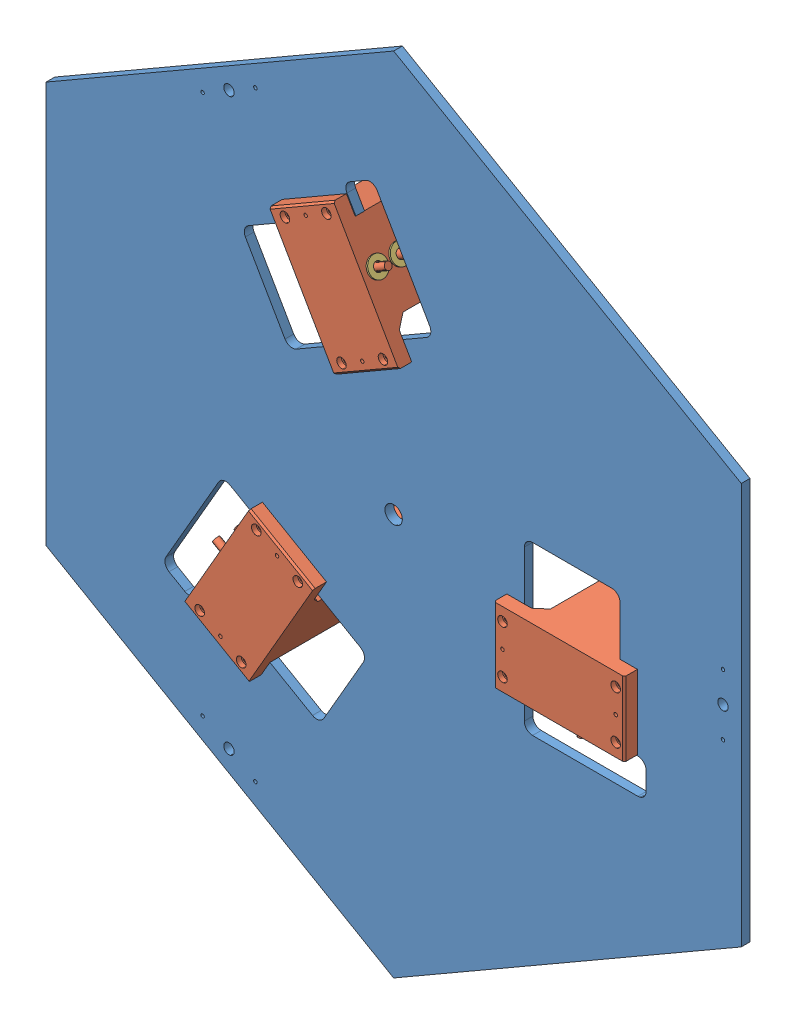
SolidWorks assembly Assemblage1, configuration Défaut. Lengths in mm.
Overall size (798.48 922 162.5).
16 component instances, 4 part files, 33 mates.
Components (placement in the parent):
- Pièce0_Plaque-1: Pièce0_Plaque [Défaut] at origin size (798.48 922 10)
- Pièce1_BlocMoteur-1: Pièce1_BlocMoteur [Défaut] at (-192.7365 -135.8294 -18) x (-0.5 -0.866025 0) z (-0.866025 0.5 0) size (152.5 162.5 100)
- Pièce1_BlocMoteur-2: Pièce1_BlocMoteur [Défaut] at (-21.2635 234.8294 -18) x (-0.5 0.866025 0) z (0.866025 0.5 0) size (152.5 162.5 100)
- Pièce1_BlocMoteur-3: Pièce1_BlocMoteur [Défaut] at (214 -99 -18) x (1 0 0) z (0 -1 0) size (152.5 162.5 100)
- Pièce1_Rendelle-1: Pièce1_Rendelle [Défaut] at (150 -101 -115) x (1 0 0) z (0 1 0) size (22 22 2)
- Pièce1_Rendelle-3: Pièce1_Rendelle [Défaut] at (12.4686 180.4038 -115) x (0.25 -0.433013 0.866025) z (-0.866025 -0.5 0) size (22 22 2)
- Pièce3_BagueBras-1: Pièce3_BagueBras [Défaut] at (-83.6603 -124.9038 -115) x (-0.866025 0.5 0) z (0 0 1) size (4 22 22)
- Pièce3_BagueBras-2: Pièce3_BagueBras [Défaut] at (150 -10 -115) x (0 -1 0) z (0 0 1) size (4 22 22)
- Pièce3_BagueBras-3: Pièce3_BagueBras [Défaut] at (-66.3397 134.9038 -115) x (0.866025 0.5 0) z (0.49419 -0.855963 0.152) size (4 22 22)
- Pièce1_Rendelle-4: Pièce1_Rendelle [Défaut] at (-162.4686 -79.4038 -115) x (0.25 0.433013 -0.866025) z (0.866025 -0.5 0) size (22 22 2)
- Pièce1_Rendelle-5: Pièce1_Rendelle [Défaut] at (-21.2635 234.8294 -18) x (0.25 -0.433013 -0.866025) z (0.866025 0.5 0) size (22 22 2)
- Pièce1_Rendelle-6: Pièce1_Rendelle [Défaut] at (-21.2635 234.8294 8) x (0.25 -0.433013 -0.866025) z (0.866025 0.5 0) size (22 22 2)
- Pièce1_Rendelle-7: Pièce1_Rendelle [Défaut] at (-192.7365 -135.8294 -18) x (0.25 0.433013 0.866025) z (-0.866025 0.5 0) size (22 22 2)
- Pièce1_Rendelle-8: Pièce1_Rendelle [Défaut] at (-192.7365 -135.8294 8) x (0.25 0.433013 0.866025) z (-0.866025 0.5 0) size (22 22 2)
- Pièce1_Rendelle-9: Pièce1_Rendelle [Défaut] at (214 -99 -18) x (1 0 0) z (0 -1 0) size (22 22 2)
- Pièce1_Rendelle-10: Pièce1_Rendelle [Défaut] at (214 -99 8) x (1 0 0) z (0 -1 0) size (22 22 2)
Mates (geometry in assembly coordinates):
- Coïncidente1: coincident anti-aligned: plane of Pièce0_Plaque-1 through (0 0 10) normal (0 0 1); plane of Pièce1_BlocMoteur-2 through (-94.8756 192.3294 10) normal (0 0 -1)
- Coïncidente2: coincident anti-aligned: plane of Pièce0_Plaque-1 through (0 0 10) normal (0 0 1); plane of Pièce1_BlocMoteur-1 through (-119.1244 -178.3294 10) normal (0 0 -1)
- Coïncidente3: coincident anti-aligned: plane of Pièce0_Plaque-1 through (0 0 10) normal (0 0 1); plane of Pièce1_BlocMoteur-3 through (214 -14 10) normal (0 0 -1)
- Coaxiale1: concentric aligned: circle of Pièce0_Plaque-1; cylinder of Pièce1_BlocMoteur-3 through (270 -29 19.5) axis (0 0 1) radius 5.5
- Coaxiale2: concentric anti-aligned: cylinder of Pièce0_Plaque-1 through (140 -84 10) axis (0 0 -1) radius 3; circle of Pièce1_BlocMoteur-3
- Coaxiale4: concentric aligned: circle of Pièce0_Plaque-1; circle of Pièce1_BlocMoteur-2
- Coaxiale5: concentric anti-aligned: circle of Pièce0_Plaque-1; circle of Pièce1_BlocMoteur-2
- Coaxiale6: concentric anti-aligned: cylinder of Pièce0_Plaque-1 through (-207.7461 -191.8269 10) axis (0 0 -1) radius 3; cylinder of Pièce1_BlocMoteur-1 through (-207.7461 -191.8269 19.5) axis (0 0 1) radius 5.5
- Coaxiale7: concentric anti-aligned: cylinder of Pièce0_Plaque-1 through (-95.1147 -106.7436 10) axis (0 0 -1) radius 3; circle of Pièce1_BlocMoteur-1
- Coïncidente5: coincident anti-aligned: plane of Pièce1_BlocMoteur-1 through (-192.7365 -135.8294 -18) normal (-0.866025 0.5 0); plane of Pièce1_Rendelle-4 through (-160.7365 -80.4038 -115) normal (0.866025 -0.5 0)
- Coaxiale9: concentric aligned: cylinder of Pièce1_BlocMoteur-1 through (-87.1244 -122.9038 -115) axis (-0.866025 0.5 0) radius 5; cylinder of Pièce1_Rendelle-4 through (-160.7365 -80.4038 -115) axis (-0.866025 0.5 0) radius 5
- Coïncidente6: coincident anti-aligned: plane of Pièce1_BlocMoteur-2 through (-21.2635 234.8294 -18) normal (0.866025 0.5 0); plane of Pièce1_Rendelle-3 through (10.7365 179.4038 -115) normal (-0.866025 -0.5 0)
- Coaxiale10: concentric aligned: cylinder of Pièce1_BlocMoteur-2 through (-62.8756 136.9038 -115) axis (0.866025 0.5 0) radius 5; cylinder of Pièce1_Rendelle-3 through (10.7365 179.4038 -115) axis (0.866025 0.5 0) radius 5
- Coïncidente7: coincident anti-aligned: plane of Pièce1_BlocMoteur-3 through (214 -99 -18) normal (0 -1 0); plane of Pièce1_Rendelle-1 through (150 -99 -115) normal (0 1 0)
- Coaxiale11: concentric aligned: cylinder of Pièce1_BlocMoteur-3 through (150 -14 -115) axis (0 -1 0) radius 5; cylinder of Pièce1_Rendelle-1 through (150 -99 -115) axis (0 -1 0) radius 5
- Coïncidente8: coincident anti-aligned: plane of Pièce1_BlocMoteur-1 through (-119.1244 -178.3294 -18) normal (0.866025 -0.5 0); plane of Pièce3_BagueBras-1 through (-87.1244 -122.9038 -115) normal (-0.866025 0.5 0)
- Coaxiale12: concentric anti-aligned: cylinder of Pièce1_BlocMoteur-1 through (-87.1244 -122.9038 -115) axis (-0.866025 0.5 0) radius 5; cylinder of Pièce3_BagueBras-1 through (-77.053 -128.7185 -115) axis (0.866025 -0.5 0) radius 5
- Coïncidente9: coincident anti-aligned: plane of Pièce1_BlocMoteur-3 through (214 -14 -18) normal (0 1 0); plane of Pièce3_BagueBras-2 through (150 -14 -115) normal (0 -1 0)
- Coaxiale13: concentric anti-aligned: cylinder of Pièce1_BlocMoteur-3 through (150 -14 -115) axis (0 -1 0) radius 5; cylinder of Pièce3_BagueBras-2 through (150 -2.3706 -115) axis (0 1 0) radius 5
- Coïncidente10: coincident anti-aligned: cylinder of Pièce1_BlocMoteur-2 through (-62.8756 136.9038 -115) axis (0.866025 0.5 0) radius 5; circle of Pièce3_BagueBras-3
- Coïncidente11: coincident anti-aligned: plane of Pièce1_BlocMoteur-2 through (-94.8756 192.3294 -18) normal (-0.866025 -0.5 0); plane of Pièce3_BagueBras-3 through (-62.8756 136.9038 -115) normal (0.866025 0.5 0)
- Coïncidente12: coincident anti-aligned: plane of Pièce1_BlocMoteur-2 through (-21.2635 234.8294 -18) normal (0.866025 0.5 0); plane of Pièce1_Rendelle-5 through (-21.2635 234.8294 -18) normal (-0.866025 -0.5 0)
- Coïncidente13: coincident anti-aligned: cylinder of Pièce1_BlocMoteur-2 through (-8.2731 242.3294 -18) axis (-0.866025 -0.5 0) radius 5; circle of Pièce1_Rendelle-5
- Coïncidente14: coincident anti-aligned: plane of Pièce1_BlocMoteur-2 through (-21.2635 234.8294 -18) normal (0.866025 0.5 0); plane of Pièce1_Rendelle-6 through (-21.2635 234.8294 8) normal (-0.866025 -0.5 0)
- Coaxiale14: concentric aligned: cylinder of Pièce1_BlocMoteur-2 through (-8.2731 242.3294 8) axis (-0.866025 -0.5 0) radius 4; cylinder of Pièce1_Rendelle-6 through (-19.5314 235.8294 8) axis (-0.866025 -0.5 0) radius 5
- Coïncidente15: coincident anti-aligned: plane of Pièce1_BlocMoteur-1 through (-192.7365 -135.8294 -18) normal (-0.866025 0.5 0); plane of Pièce1_Rendelle-8 through (-192.7365 -135.8294 8) normal (0.866025 -0.5 0)
- Coïncidente16: coincident anti-aligned: plane of Pièce1_BlocMoteur-1 through (-192.7365 -135.8294 -18) normal (-0.866025 0.5 0); plane of Pièce1_Rendelle-7 through (-192.7365 -135.8294 -18) normal (0.866025 -0.5 0)
- Coïncidente17: coincident anti-aligned: cylinder of Pièce1_BlocMoteur-1 through (-205.7269 -128.3294 -18) axis (0.866025 -0.5 0) radius 5; circle of Pièce1_Rendelle-7
- Coaxiale15: concentric anti-aligned: cylinder of Pièce1_BlocMoteur-1 through (-205.7269 -128.3294 8) axis (0.866025 -0.5 0) radius 4; circle of Pièce1_Rendelle-8
- Coïncidente18: coincident anti-aligned: plane of Pièce1_BlocMoteur-3 through (214 -99 -18) normal (0 -1 0); plane of Pièce1_Rendelle-10 through (214 -99 8) normal (0 1 0)
- Coaxiale16: concentric anti-aligned: cylinder of Pièce1_BlocMoteur-3 through (214 -114 8) axis (0 1 0) radius 4; circle of Pièce1_Rendelle-10
- Coïncidente19: coincident: plane of Pièce1_BlocMoteur-3 through (214 -99 -18) normal (0 -1 0); circle of Pièce1_Rendelle-9
- Coïncidente21: coincident anti-aligned: cylinder of Pièce1_BlocMoteur-3 through (214 -114 -18) axis (0 1 0) radius 5; circle of Pièce1_Rendelle-9
